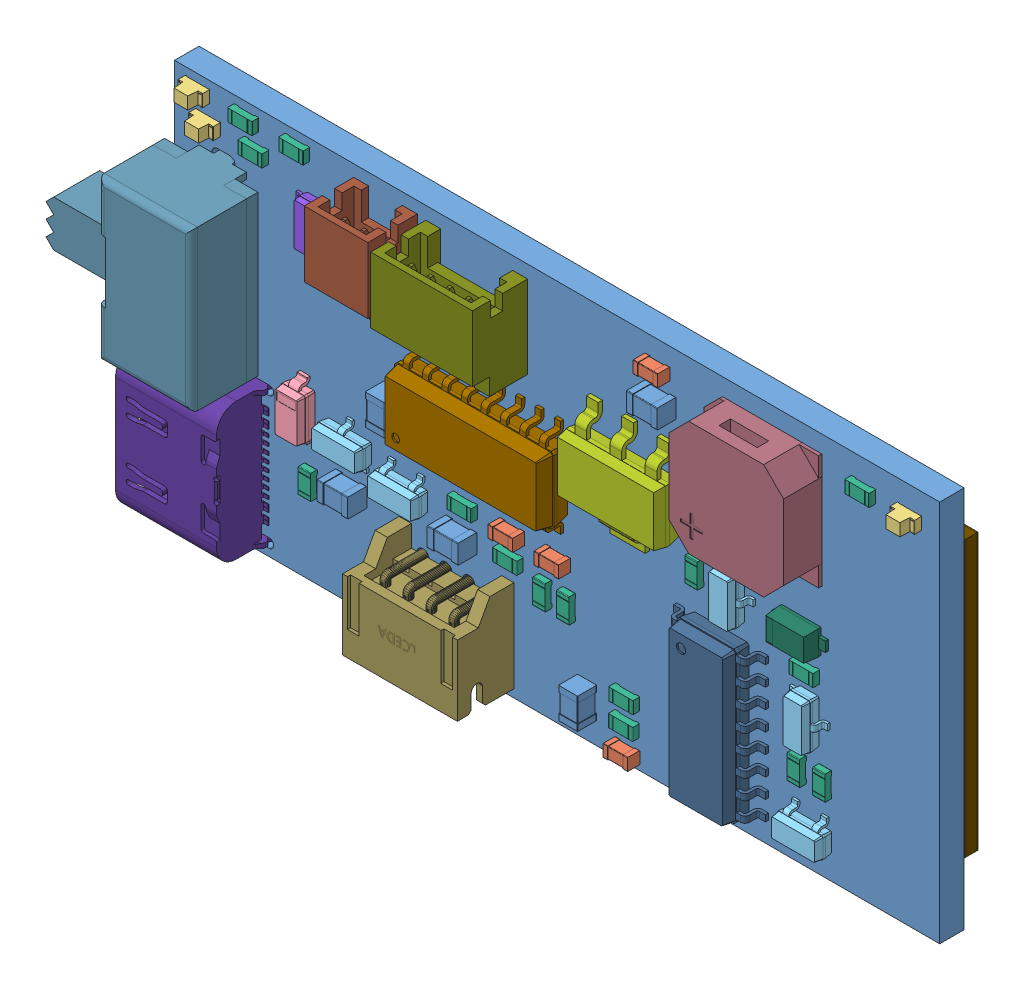
SolidWorks assembly GripMeter2, configuration Predeterminado. Lengths in mm.
Overall size (53.85 25 9.71).
91 component instances, 19 part files, 0 mates.
Components (placement in the parent):
- C_0805_2012Metric-1: C_0805_2012Metric [Predeterminado] at (111.61 -143.4 1.65) x (-1 0 0) z (0 0 1) size (2 1.25 1.25)
  - SOLID-1: SOLID [Predeterminado] at origin size (2 1.25 1.25)
- C_0805_2012Metric-2: C_0805_2012Metric [Predeterminado] at (131.83 -128.25 1.65) size (2 1.25 1.25)
  - SOLID-1: SOLID [Predeterminado] at origin size (2 1.25 1.25)
- C_0603_1608Metric-1: C_0603_1608Metric [Predeterminado] at (131.61 -126.52 1.65) size (1.6 0.8 0.8)
  - SOLID_2-1: SOLID_2 [Predeterminado] at origin size (1.6 0.8 0.8)
- C_0805_2012Metric-3: C_0805_2012Metric [Predeterminado] at (118.81 -142.41 1.65) size (2 1.25 1.25)
  - SOLID-1: SOLID [Predeterminado] at origin size (2 1.25 1.25)
- C_0603_1608Metric-2: C_0603_1608Metric [Predeterminado] at (122.13 -140.57 1.65) size (1.6 0.8 0.8)
  - SOLID_2-1: SOLID_2 [Predeterminado] at origin size (1.6 0.8 0.8)
- C_0603_1608Metric-3: C_0603_1608Metric [Predeterminado] at (125.13 -140.58 1.65) size (1.6 0.8 0.8)
  - SOLID_2-1: SOLID_2 [Predeterminado] at origin size (1.6 0.8 0.8)
- C_0805_2012Metric-4: C_0805_2012Metric [Predeterminado] at (114.38 -137.23 1.65) x (0 1 0) z (0 0 1) size (2 1.25 1.25)
  - SOLID-1: SOLID [Predeterminado] at origin size (2 1.25 1.25)
- LED_0603_1608Metric-1: LED_0603_1608Metric [Predeterminado] at (102.26 -127.36 1.65) size (1.6 0.8 1.1)
  - SOLID_3-1: SOLID_3 [Predeterminado] at origin size (1.6 0.8 1.1)
- D_SOD-123-1: D_SOD-123 [Predeterminado] at (108.58 -140.29 1.65) x (0 -1 0) z (0 0 1) size (3.8 1.6 1.25)
  - SOLID_4-1: SOLID_4 [Predeterminado] at origin size (3.8 1.6 1.25)
- SOT-23-1: SOT-23 [Predeterminado] at (141.62 -141.23 1.65) size (2.5 3 1.2)
  - SOLID_5-1: SOLID_5 [Predeterminado] at origin size (2.5 3 1.2)
- SOT-23-2: SOT-23 [Predeterminado] at (141.66 -147.65 1.65) x (0 -1 0) z (0 0 1) size (2.5 3 1.2)
  - SOLID_5-1: SOLID_5 [Predeterminado] at origin size (2.5 3 1.2)
- SOT-23-3: SOT-23 [Predeterminado] at (111.6 -140.68 1.65) x (0 1 0) z (0 0 1) size (2.5 3 1.2)
  - SOLID_5-1: SOLID_5 [Predeterminado] at origin size (2.5 3 1.2)
- R_0603_1608Metric-1: R_0603_1608Metric [Predeterminado] at (140.93 -144.46 1.65) x (0 -1 0) z (0 0 1) size (1.6 0.8 0.45)
  - SOLID_6-1: SOLID_6 [Predeterminado] at origin size (1.6 0.8 0.45)
- R_0603_1608Metric-2: R_0603_1608Metric [Predeterminado] at (141.425 -138.75 1.65) x (-1 0 0) z (0 0 1) size (1.6 0.8 0.45)
  - SOLID_6-1: SOLID_6 [Predeterminado] at origin size (1.6 0.8 0.45)
- R_0603_1608Metric-3: R_0603_1608Metric [Predeterminado] at (142.59 -144.46 1.65) x (0 -1 0) z (0 0 1) size (1.6 0.8 0.45)
  - SOLID_6-1: SOLID_6 [Predeterminado] at origin size (1.6 0.8 0.45)
- R_0603_1608Metric-4: R_0603_1608Metric [Predeterminado] at (108.09 -125.85 1.65) size (1.6 0.8 0.45)
  - SOLID_6-1: SOLID_6 [Predeterminado] at origin size (1.6 0.8 0.45)
- R_0603_1608Metric-5: R_0603_1608Metric [Predeterminado] at (105.42 -127.35 1.65) x (-1 0 0) z (0 0 1) size (1.6 0.8 0.45)
  - SOLID_6-1: SOLID_6 [Predeterminado] at origin size (1.6 0.8 0.45)
- R_0603_1608Metric-6: R_0603_1608Metric [Predeterminado] at (108.98 -144.25 1.65) x (0 -1 0) z (0 0 1) size (1.6 0.8 0.45)
  - SOLID_6-1: SOLID_6 [Predeterminado] at origin size (1.6 0.8 0.45)
- R_0603_1608Metric-7: R_0603_1608Metric [Predeterminado] at (124.3 -142.84 1.65) x (0 -1 0) z (0 0 1) size (1.6 0.8 0.45)
  - SOLID_6-1: SOLID_6 [Predeterminado] at origin size (1.6 0.8 0.45)
- R_0603_1608Metric-8: R_0603_1608Metric [Predeterminado] at (125.86 -142.8 1.65) x (0 -1 0) z (0 0 1) size (1.6 0.8 0.45)
  - SOLID_6-1: SOLID_6 [Predeterminado] at origin size (1.6 0.8 0.45)
- R_0603_1608Metric-9: R_0603_1608Metric [Predeterminado] at (119.075 -140.6 1.65) size (1.6 0.8 0.45)
  - SOLID_6-1: SOLID_6 [Predeterminado] at origin size (1.6 0.8 0.45)
- R_0603_1608Metric-10: R_0603_1608Metric [Predeterminado] at (122.06 -142.08 1.65) size (1.6 0.8 0.45)
  - SOLID_6-1: SOLID_6 [Predeterminado] at origin size (1.6 0.8 0.45)
- SOT-223-1: SOT-223 [Predeterminado] at (129.92 -133.71 1.65) x (0 -1 0) z (0 0 1) size (7 6.5 1.7)
  - SOLID_7-1: SOLID_7 [Predeterminado] at origin size (7 6.5 1.7)
- TSOT-23-5-1: TSOT-23-5 [Predeterminado] at (109.52 -129.37 1.65) x (-1 0 0) z (0 0 1) size (2.8 2.9 0.95)
  - SOLID_8-1: SOLID_8 [Predeterminado] at origin size (2.8 2.9 0.95)
- SOP-16_4.4x10.4mm_P1.27mm-1: SOP-16_4.4x10.4mm_P1.27mm [Predeterminado] at (120.83 -135.77 1.65) x (0 1 0) z (0 0 1) size (6.4 10.4 2.1)
  - SOLID_9-1: SOLID_9 [Predeterminado] at origin size (6.4 10.4 2.1)
- SOIC-16_3.9x9.9mm_P1.27mm-1: SOIC-16_3.9x9.9mm_P1.27mm [Predeterminado] at (135.86 -143.9 1.65) size (6 9.9 1.75)
  - SOLID_10-1: SOLID_10 [Predeterminado] at origin size (6 9.9 1.75)
- df13-2p-1_25ds_50_-1: df13-2p-1_25ds_50_ [Predeterminado] at (98.16 -128.54 28.65) x (0 0 1) z (-1 0 0) size (5.9 5.4 4.15)
  - COMPOUND-1: COMPOUND [Predeterminado] at origin size (5.9 5.4 4.15)
- jst_zh_1_5mm_4d-1: jst_zh_1_5mm_4d [Predeterminado] at (118.48 -146.42 1.65) size (7.5 6 6.48)
  - COMPOUND_2-1: COMPOUND_2 [Predeterminado] at origin size (7.5 6 6.48)
- LED_0603_1608Metric-2: LED_0603_1608Metric [Predeterminado] at (101.56 -125.84 1.65) x (-1 0 0) z (0 0 1) size (1.6 0.8 1.1)
  - SOLID_3-1: SOLID_3 [Predeterminado] at origin size (1.6 0.8 1.1)
- SOT-23-4: SOT-23 [Predeterminado] at (115.26 -141.56 1.65) x (0 -1 0) z (0 0 1) size (2.5 3 1.2)
  - SOLID_5-1: SOLID_5 [Predeterminado] at origin size (2.5 3 1.2)
- R_0603_1608Metric-11: R_0603_1608Metric [Predeterminado] at (104.75 -125.85 1.65) size (1.6 0.8 0.45)
  - SOLID_6-1: SOLID_6 [Predeterminado] at origin size (1.6 0.8 0.45)
- User Library-YX7525P-1: User Library-YX7525P [Predeterminado] at (138.6 -129.83 1.65) size (7.56 7.56 2.51)
  - SOLID_11-1: SOLID_11 [Predeterminado] at origin size (7.56 7.56 2.51)
- LED_0603_1608Metric-3: LED_0603_1608Metric [Predeterminado] at (148.09 -126.72 1.65) x (-1 0 0) z (0 0 1) size (1.6 0.8 1.1)
  - SOLID_3-1: SOLID_3 [Predeterminado] at origin size (1.6 0.8 1.1)
- R_0603_1608Metric-12: R_0603_1608Metric [Predeterminado] at (145.09 -126.72 1.65) size (1.6 0.8 0.45)
  - SOLID_6-1: SOLID_6 [Predeterminado] at origin size (1.6 0.8 0.45)
- User Library-SK-22D02-PG4-1: User Library-SK-22D02-PG4 [Predeterminado] at (103.2 -134.14 1.65) x (0 1 0) z (0 0 1) size (10.4 10.1 7.6)
  - COMPOUND_3-1: COMPOUND_3 [Predeterminado] at origin size (10.4 10.1 7.6)
- C_0805_2012Metric-5: C_0805_2012Metric [Predeterminado] at (127.01 -147.52 1.65) x (0 -1 0) z (0 0 1) size (2 1.25 1.25)
  - SOLID-1: SOLID [Predeterminado] at origin size (2 1.25 1.25)
- R_0603_1608Metric-13: R_0603_1608Metric [Predeterminado] at (129.64 -147.69 1.65) x (-1 0 0) z (0 0 1) size (1.6 0.8 0.45)
  - SOLID_6-1: SOLID_6 [Predeterminado] at origin size (1.6 0.8 0.45)
- R_0603_1608Metric-14: R_0603_1608Metric [Predeterminado] at (129.65 -146.17 1.65) size (1.6 0.8 0.45)
  - SOLID_6-1: SOLID_6 [Predeterminado] at origin size (1.6 0.8 0.45)
- D_SOD-123F-1: D_SOD-123F [Predeterminado] at (141.02 -136.69 1.65) size (3.5 1.6 1.1)
  - SOLID_12-1: SOLID_12 [Predeterminado] at origin size (3.5 1.6 1.1)
- SOT-23-5: SOT-23 [Predeterminado] at (136.76 -136.63 1.65) size (2.5 3 1.2)
  - SOLID_5-1: SOLID_5 [Predeterminado] at origin size (2.5 3 1.2)
- R_0603_1608Metric-15: R_0603_1608Metric [Predeterminado] at (134.25 -136.63 1.65) x (0 1 0) z (0 0 1) size (1.6 0.8 0.45)
  - SOLID_6-1: SOLID_6 [Predeterminado] at origin size (1.6 0.8 0.45)
- df13-4p-1_25ds_50_-1: df13-4p-1_25ds_50_ [Predeterminado] at (105.5 -128.48 29.15) x (0 0 1) z (-1 0 0) size (5.9 5.4 6.65)
  - COMPOUND_4-1: COMPOUND_4 [Predeterminado] at origin size (5.9 5.4 6.65)
- DX07S016JA1-V1_JAE_Proprietary-1: DX07S016JA1-V1_JAE_Proprietary [Predeterminado] at (103.97 -144.91 3.15) x (0 -1 0) z (0 0 1) size (8.94 6.9 4.06)
  - SOLID_13-1: SOLID_13 [Predeterminado] at origin size (8.94 6.9 4.06)
- C_0603_1608Metric-4: C_0603_1608Metric [Predeterminado] at (129.65 -149.21 1.65) x (-1 0 0) z (0 0 1) size (1.6 0.8 0.8)
  - SOLID_2-1: SOLID_2 [Predeterminado] at origin size (1.6 0.8 0.8)
- User Library-ESP321-1: User Library-ESP321 [Predeterminado] at (137.2 -137 -0.05) x (0 1 0) z (0 0 -1) size (18 25.5 2.92)
  - COMPOUND_5-1: COMPOUND_5 [Predeterminado] at origin size (18 25.5 2.92)
- _autosave-GripMeter PCB-1: _autosave-GripMeter PCB [Predeterminado] at origin size (50 25 1.6)
